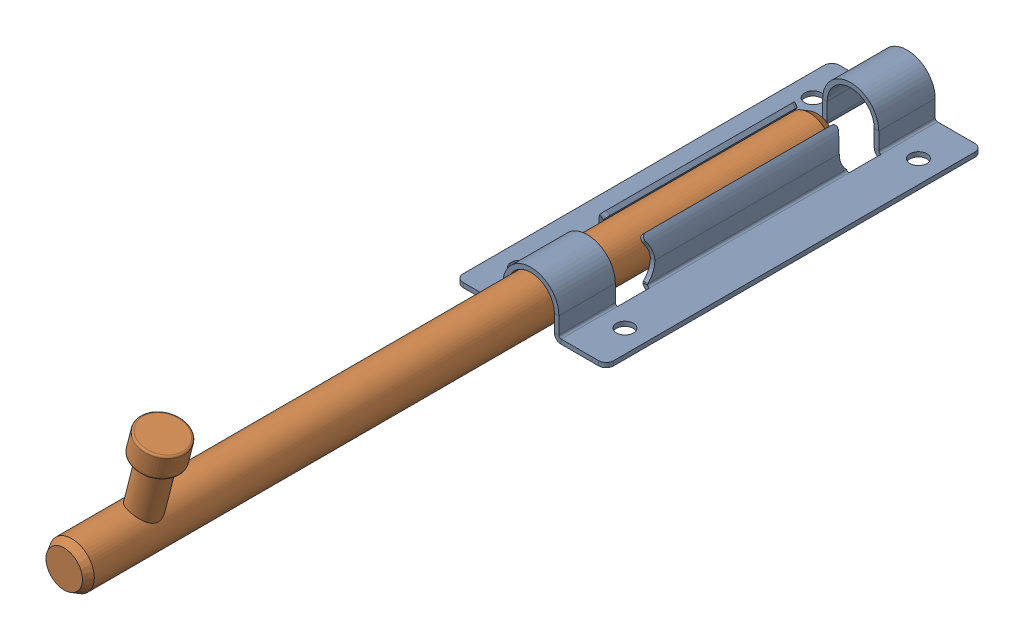
SolidWorks assembly Assem11, configuration Default. Lengths in mm.
Overall size (40 33.01 224).
2 component instances, 2 part files, 5 mates.
Components (placement in the parent):
- zapah 3-1: zapah 3 [Default] at (-83.5048 10.2401 48.2592) size (40 13.7 100)
- zapah 1-1: zapah 1 [Default] at (-83.5048 16.4901 172.2592) x (0.968652 -0.248423 0) z (0 0 1) size (12 31 200)
Mates (geometry in assembly coordinates):
- Concentric1: concentric aligned: cylinder of zapah 3-1 through (-83.5048 16.4901 150.5555) axis (0 0 -1) radius 6.25; cylinder of zapah 1-1 through (-83.5048 16.4901 22.2592) axis (0 0 -1) radius 6
- LimitDistance2: limit distance = 100 mm: plane of zapah 3-1 through (-83.5048 16.4901 98.2592) normal (0 0 1); cylinder of zapah 1-1 through (-77.2942 40.7064 202.2592) axis (-0.248423 -0.968652 0) radius 4
- Parallel2: parallel aligned: plane of zapah 2-2 through (-90.9548 16.4901 -41.7408) normal (-1 0 0); plane of zapah 3-1 through (-90.9548 16.4901 -1.7408) normal (-1 0 0)
- Concentric2: concentric aligned: cylinder of zapah 1-1 through (-83.5048 16.4901 22.2592) axis (0 0 1) radius 6; cylinder of zapah 2-2 through (-83.5048 16.4901 -41.7408) axis (0 0 1) radius 6.25
- Distance1: distance = 10 mm anti-aligned: plane of zapah 2-2 through (-83.5048 16.4901 -11.7408) normal (0 0 1); plane of zapah 3-1 through (-83.5048 16.4901 -1.7408) normal (0 0 -1)
